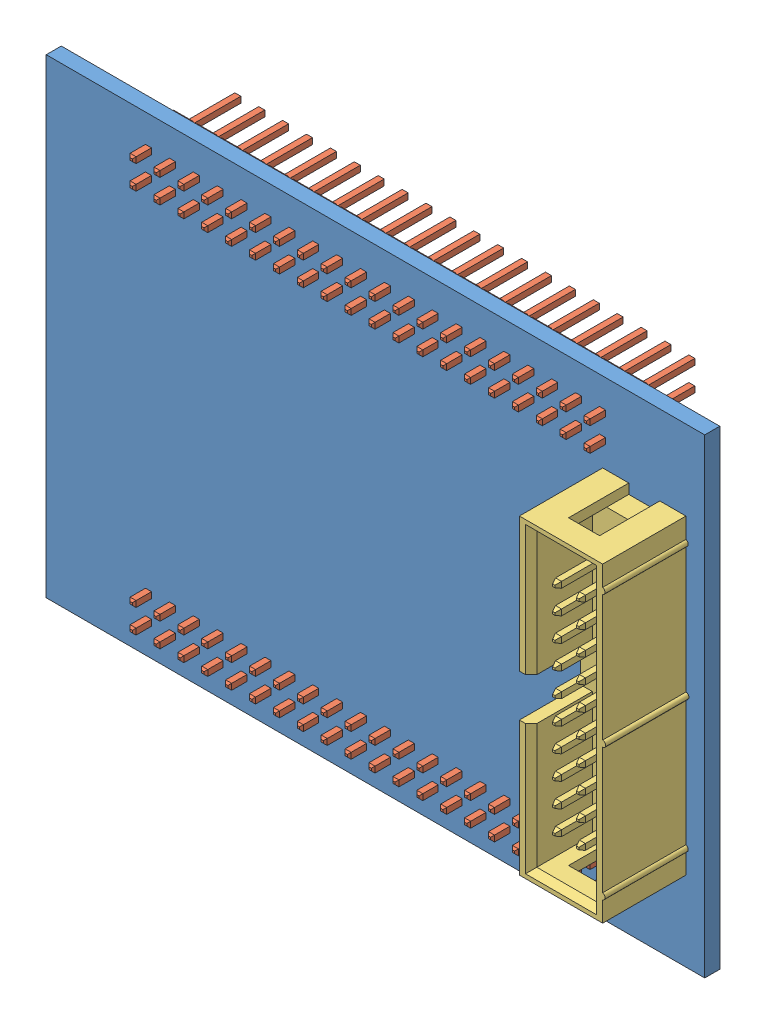
SolidWorks assembly STM32-H107 Assembly, configuration Default. Lengths in mm.
Overall size (70 50 18.55).
4 component instances, 3 part files, 9 mates.
Components (placement in the parent):
- STM32-H107 PCB-1: STM32-H107 PCB [Default] at (-11.1637 11.3867 54.2382) size (70 50 1.6)
- 2x20-HDR-1: 2x20-HDR [Default] at (23.8363 17.2267 53.4061) x (1 0 0) z (0 1 0) size (50.8 11.54 5.08)
- 2x20-HDR-2: 2x20-HDR [Default] at (23.8363 58.0867 53.4061) x (1 0 0) z (0 1 0) size (50.8 11.54 5.08)
- 2x10 boxed HDR-1: 2x10 boxed HDR [Default] at (52.4113 36.3867 60.2632) x (0 -1 0) z (0 0 1) size (33.06 9.18 12.1)
Mates (geometry in assembly coordinates):
- Coincident1: coincident anti-aligned: plane of STM32-H107 PCB-1 through (-11.1637 11.3867 54.2382) normal (0 0 -1); plane of 2x20-HDR-1 through (-1.2302 18.1567 54.2382) normal (0 0 1)
- Coincident2: coincident anti-aligned: plane of STM32-H107 PCB-1 through (-11.1637 11.3867 54.2382) normal (0 0 -1); plane of 2x20-HDR-2 through (-1.2302 59.0167 54.2382) normal (0 0 1)
- Distance3: distance = 2.98 mm aligned: plane of 2x20-HDR-1 through (47.9663 14.3667 51.9061) normal (0 -1 0); plane of STM32-H107 PCB-1 through (-11.1637 11.3867 55.8382) normal (0 -1 0)
- Distance4: distance = 10.55 mm aligned: plane of 2x20-HDR-1 through (-0.6137 14.3667 57.6761) normal (-1 0 0); plane of STM32-H107 PCB-1 through (-11.1637 11.3867 55.8382) normal (-1 0 0)
- Distance5: distance = 2.98 mm aligned: plane of 2x20-HDR-2 through (42.8863 58.4067 51.9061) normal (0 1 0); plane of STM32-H107 PCB-1 through (-11.1637 61.3867 55.8382) normal (0 1 0)
- Distance6: distance = 10.55 mm aligned: plane of 2x20-HDR-2 through (-0.6137 57.7667 57.6761) normal (-1 0 0); plane of STM32-H107 PCB-1 through (-11.1637 11.3867 55.8382) normal (-1 0 0)
- Coincident3: coincident: plane of STM32-H107 PCB-1 through (-11.1637 11.3867 55.8382) normal (0 0 1); plane of 2x10 boxed HDR-1 through (47.9863 25.9587 55.8382) normal (0 0 -1)
- Distance7: distance = 2 mm: plane of 2x10 boxed HDR-1 through (56.8363 36.3867 60.2632) normal (1 0 0); plane of STM32-H107 PCB-1 through (58.8363 11.3867 55.8382) normal (1 0 0)
- Distance8: distance = 22.75 mm anti-aligned: plane of 2x10 boxed HDR-1 through (47.9863 38.6367 58.1882) normal (0 -1 0); plane of STM32-H107 PCB-1 through (-11.1637 61.3867 55.8382) normal (0 1 0)
